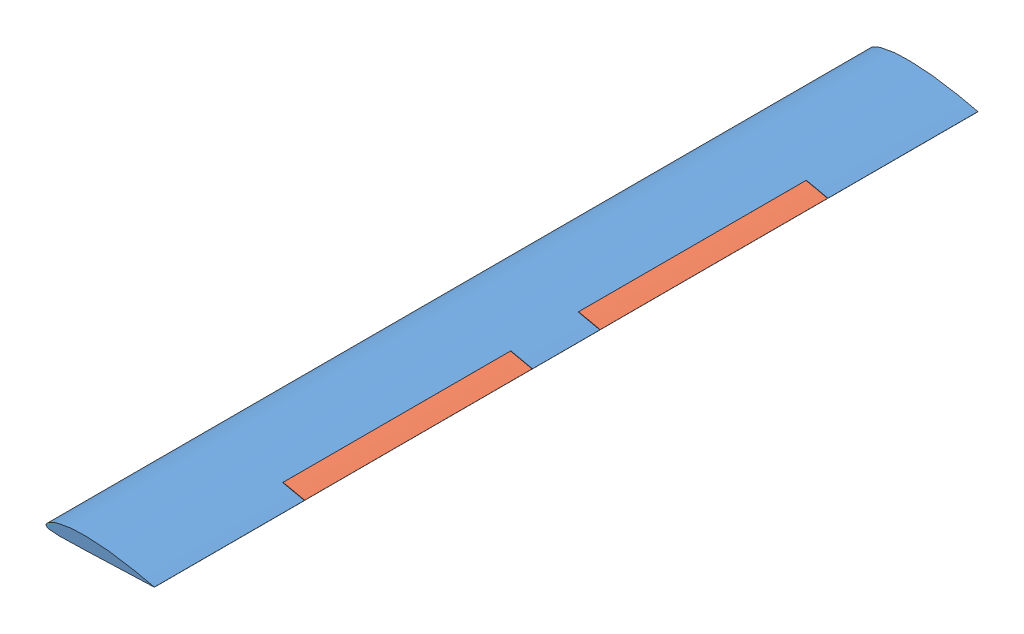
SolidWorks assembly Wing with flap clark y, configuration Default. Lengths in mm.
Overall size (164.12 20 1246.6).
3 component instances, 2 part files, 4 mates.
Components (placement in the parent):
- Wing_clark y-1: Wing_clark y [Default] at (-139.163 5.3912 -600.2268) size (164.12 20 1246.6)
- Flap_clark y-1: Flap_clark y [Default] at (-139.2407 5.3972 74.5732) size (36.96 8.48 344.25)
- Flap_clark y-2: Flap_clark y [Default] at (-139.2407 5.3972 -372.6768) size (36.96 8.48 344.25)
Mates (geometry in assembly coordinates):
- Concentric1: concentric: cylinder of Wing_clark y-1 through (-4.963 8.3383 64.0732) axis (0 0 1) radius 2; cylinder of Flap_clark y-1 through (-4.963 8.3383 488.2633) axis (0 0 -1) radius 2
- Distance3: distance = 0.5 mm anti-aligned: plane of Wing_clark y-1 through (24.837 65.3912 419.3232) normal (0 0 -1); plane of Flap_clark y-1 through (38.9505 249.9972 418.8232) normal (0 0 1)
- Concentric2: concentric: cylinder of Wing_clark y-1 through (-4.963 8.3383 -17.9268) axis (0 0 -1) radius 2; cylinder of Flap_clark y-2 through (-4.963 8.3383 67.5732) axis (0 0 -1) radius 2
- Distance4: distance = 0.5 mm anti-aligned: plane of Flap_clark y-2 through (38.9505 249.9972 -28.4268) normal (0 0 1); plane of Wing_clark y-1 through (24.837 65.3912 -27.9268) normal (0 0 -1)
